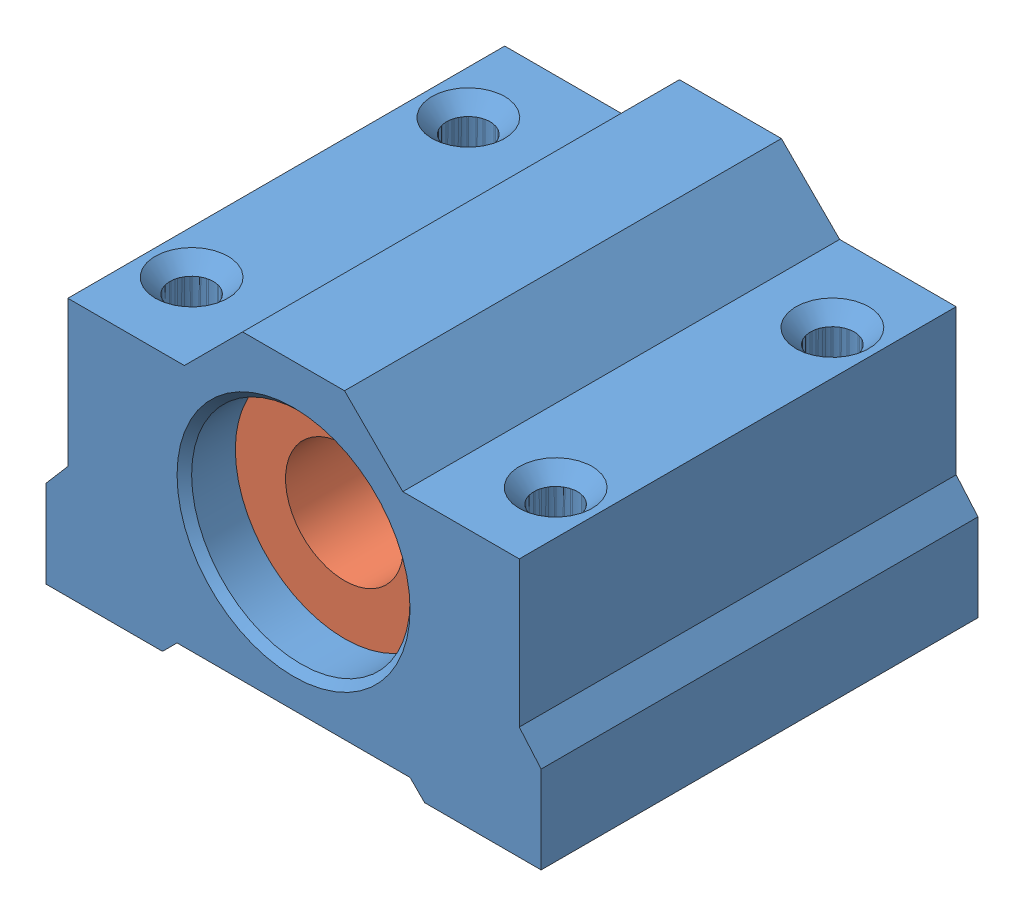
SolidWorks assembly Ball Bearing Assemby, configuration Default. Lengths in mm.
Overall size (34 21.75 30).
2 component instances, 2 part files, 2 mates.
Components (placement in the parent):
- Ball Bearing Slider-1: Ball Bearing Slider [Default] at origin size (34 21.75 30)
- Ball Bearing Imaginary Inlay-1: Ball Bearing Imaginary Inlay [Default] at (17 11 3.5) size (15 15 23)
Mates (geometry in assembly coordinates):
- Concentric1: concentric: cylinder of Ball Bearing Slider-1 through (17 11 30) axis (0 0 1) radius 7.5; cylinder of Ball Bearing Imaginary Inlay-1 through (17 11 26.5) axis (0 0 -1) radius 7.5
- Distance1: distance = 3.5 mm: plane of Ball Bearing Imaginary Inlay-1 through (17 11 26.5) normal (0 0 1); plane of Ball Bearing Slider-1 through (0 0 30) normal (0 0 1)
